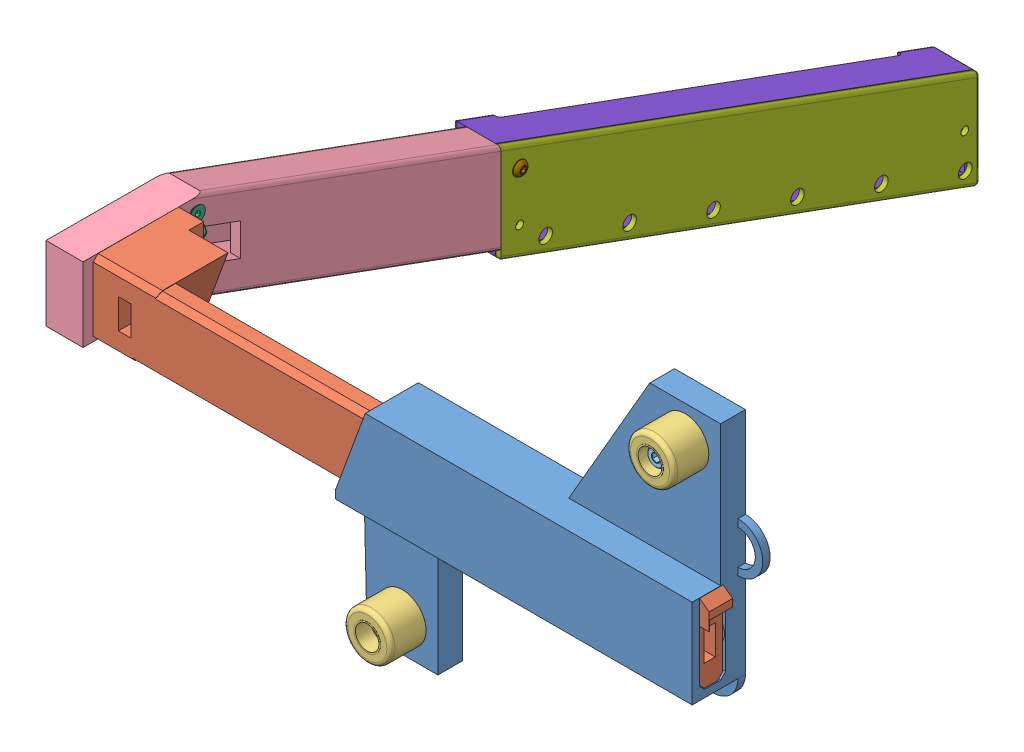
SolidWorks assembly ac_chuni, configuration Default. Lengths in mm.
Overall size (826.3 247 363.49).
11 component instances, 9 part files, 19 mates.
Components (placement in the parent):
- slider-1: slider [Default] at (325.8438 341.2973 585.5072) size (750 197 21.5)
- slider_rail-1: slider_rail [Default] at (249.5461 341.2973 586.5072) size (750 197 34.5)
- 8884T21_Heavy Duty Unthreaded Bumpers-1: 8884T21_Heavy Duty Unthreaded Bumpers [8884T21] at (166.3 491.8473 595.4447) x (1 0 0) z (0 -1 0) size (19.05 14.29 19.05)
- 8884T21_Heavy Duty Unthreaded Bumpers-2: 8884T21_Heavy Duty Unthreaded Bumpers [8884T21] at (52 373.0473 595.4447) x (1 0 0) z (0 -1 0) size (19.05 14.29 19.05)
- air_tower-1: air_tower [Default] at (-64.6441 415.2973 596.007) x (0 1 0) z (-0.999996 0 -0.002899) size (149.72 358.64 15)
- 91292A118_18-8 Stainless Steel Socket Head Screw-1: 91292A118_18-8 Stainless Steel Socket Head Screw [91292A118] at (166.3 491.8473 579.4447) x (0.419822 0.907607 0) z (0 0 -1) size (7 7 20.35)
- 92125A103_18-8 Stainless Steel Hex Drive Flat Head Screw-1: 92125A103_18-8 Stainless Steel Hex Drive Flat Head Screw [92125A103] at (-63.1698 440.2973 555.0611) x (0.002899 0.013946 -0.999899) z (0.999996 0 0.002899) size (6 6 15.33)
- air_tower_top_1-1: air_tower_top_1 [Default] at (-64.6441 415.2973 596.007) x (0 1 0) z (-0.999996 0 -0.002899) size (154 331.92 2)
- air_tower_top_2-1: air_tower_top_2 [Default] at (-83.8913 415.2973 595.9512) x (0 1 0) z (-0.999996 0 -0.002899) size (109.68 193.14 17)
- 94500A266_316 Stainless Steel Button Head Hex Drive Screws-1: 94500A266_316 Stainless Steel Button Head Hex Drive Screws [94500A266] at (-62.4954 390.475 424.0125) x (0.002899 0 -0.999996) z (0.999996 0 0.002899) size (5.7 5.7 22.02)
- 92125A103_18-8 Stainless Steel Hex Drive Flat Head Screw-2: 92125A103_18-8 Stainless Steel Hex Drive Flat Head Screw [92125A103] at (-58.0941 440.2973 559.6773) x (-0.001543 0.999999 0) z (0 0 -1) size (6 6 15.33)
Mates (geometry in assembly coordinates):
- Concentric1: concentric aligned: cylinder of slider-1 through (166.3 491.8473 587.5072) axis (0 0 -1) radius 2.05; cylinder of 8884T21_Heavy Duty Unthreaded Bumpers-1 through (166.3 491.8473 601.7947) axis (0 0 -1) radius 2.3813
- Coincident1: coincident anti-aligned: plane of slider-1 through (325.8438 341.2973 587.5072) normal (0 0 1); plane of 8884T21_Heavy Duty Unthreaded Bumpers-1 through (166.3 491.8473 587.5072) normal (0 0 -1)
- Concentric2: concentric aligned: cylinder of slider-1 through (52 373.0473 587.5072) axis (0 0 -1) radius 2.05; cylinder of 8884T21_Heavy Duty Unthreaded Bumpers-2 through (52 373.0473 601.7947) axis (0 0 -1) radius 2.3813
- Coincident2: coincident anti-aligned: plane of slider-1 through (325.8438 341.2973 587.5072) normal (0 0 1); plane of 8884T21_Heavy Duty Unthreaded Bumpers-2 through (52 373.0473 587.5072) normal (0 0 -1)
- Coincident3: coincident anti-aligned: plane of slider-1 through (36.3393 445.2973 596.0072) normal (0 -1 0); plane of slider_rail-1 through (249.5461 445.2973 596.0072) normal (0 1 0)
- Coincident4: coincident anti-aligned: plane of slider-1 through (36.3393 415.2973 596.0072) normal (0 0 -1); plane of slider_rail-1 through (249.5461 341.2973 596.0072) normal (0 0 1)
- Coincident5: coincident anti-aligned: line of slider_rail-1 through (-64.5441 445.2973 561.5072) axis (0 -1 0); line of air_tower-1 through (-64.5441 361.4297 561.5072) axis (0 1 0)
- Coincident8: coincident aligned: plane of slider_rail-1 through (249.5461 445.2973 596.0072) normal (0 1 0); plane of air_tower-1 through (-79.644 445.2973 595.9635) normal (0 1 0)
- Concentric3: concentric aligned: cylinder of 8884T21_Heavy Duty Unthreaded Bumpers-1 through (166.3 491.8473 615.265) axis (0 0 -1) radius 4.7625; cylinder of 91292A118_18-8 Stainless Steel Socket Head Screw-1 through (166.3 491.8473 599.4447) axis (0 0 -1) radius 3.5
- Coincident9: coincident anti-aligned: plane of 8884T21_Heavy Duty Unthreaded Bumpers-1 through (166.3 491.8473 595.4447) normal (0 0 1); plane of 91292A118_18-8 Stainless Steel Socket Head Screw-1 through (166.3 491.8473 595.4447) normal (0 0 -1)
- Concentric4: concentric aligned: cylinder of air_tower-1 through (-79.5253 440.2973 555.0137) axis (0.999996 0 0.002899) radius 1.55; cylinder of 92125A103_18-8 Stainless Steel Hex Drive Flat Head Screw-1 through (-63.1698 440.2973 555.0611) axis (0.999996 0 0.002899) radius 3
- Coincident10: coincident anti-aligned: plane of air_tower-1 through (-66.6441 415.2973 596.0012) normal (0.999996 0 0.002899); plane of air_tower_top_1-1 through (-66.6441 415.2973 596.0012) normal (-0.999996 0 -0.002899)
- Concentric5: concentric aligned: cylinder of air_tower-1 through (-118.0591 390.475 423.8514) axis (0.999996 0 0.002899) radius 1.6; cylinder of air_tower_top_1-1 through (-66.1454 390.475 424.0019) axis (0.999996 0 0.002899) radius 1.6
- Concentric6: concentric aligned: cylinder of air_tower-1 through (-118.0591 370.475 423.8514) axis (0.999996 0 0.002899) radius 1.6; cylinder of air_tower_top_1-1 through (-66.1454 370.475 424.0019) axis (0.999996 0 0.002899) radius 1.6
- Concentric7: concentric anti-aligned: cylinder of air_tower_top_1-1 through (-65.6253 313.9978 244.5912) axis (0.999996 0 0.002899) radius 1.6; cylinder of air_tower_top_2-1 through (-65.8726 313.9978 244.5905) axis (-0.999996 0 -0.002899) radius 1.6
- Concentric8: concentric anti-aligned: cylinder of air_tower_top_1-1 through (-66.1454 370.475 424.0019) axis (0.999996 0 0.002899) radius 1.6; cylinder of air_tower_top_2-1 through (-77.3927 370.475 423.9693) axis (-0.999996 0 -0.002899) radius 1.6
- Concentric9: concentric aligned: cylinder of air_tower_top_1-1 through (-66.1454 390.475 424.0019) axis (0.999996 0 0.002899) radius 1.6; cylinder of 94500A266_316 Stainless Steel Button Head Hex Drive Screws-1 through (-62.4954 390.475 424.0125) axis (0.999996 0 0.002899) radius 2.85
- Coincident13: coincident anti-aligned: plane of air_tower_top_1-1 through (-64.6441 415.2973 596.007) normal (0.999996 0 0.002899); plane of 94500A266_316 Stainless Steel Button Head Hex Drive Screws-1 through (-64.1537 387.625 426.8677) normal (-0.999996 0 -0.002899)
- Concentric10: concentric aligned: cylinder of slider_rail-1 through (-58.0941 440.2973 577.5072) axis (0 0 -1) radius 1.75; cylinder of 92125A103_18-8 Stainless Steel Hex Drive Flat Head Screw-2 through (-58.0941 440.2973 559.6773) axis (0 0 -1) radius 3
